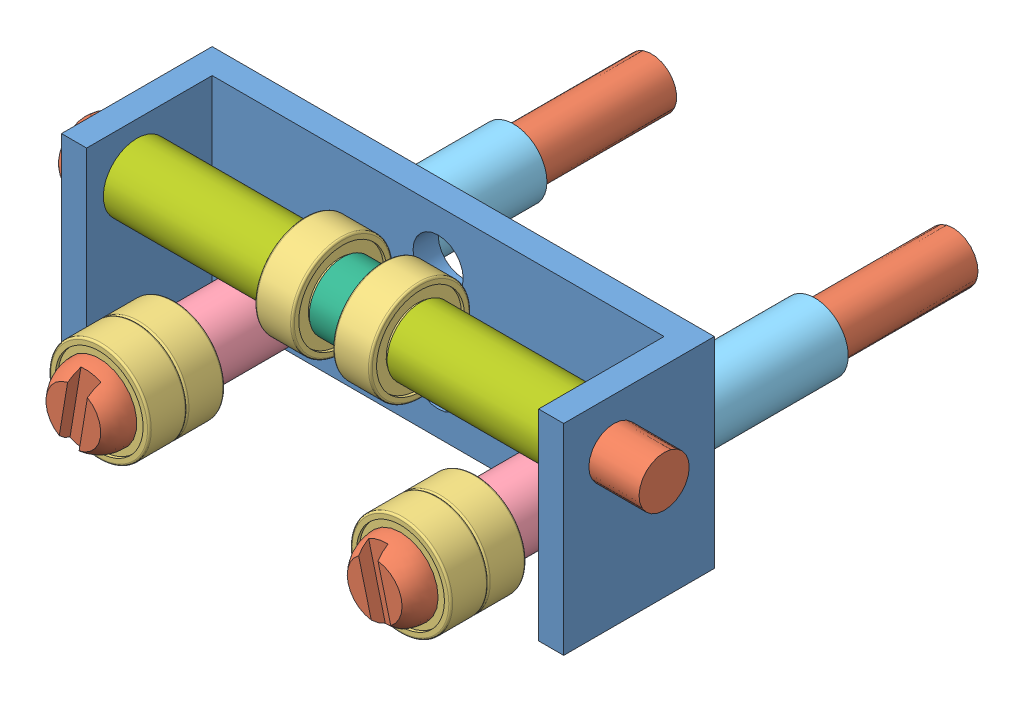
SolidWorks assembly BearingCarriageAssembly, configuration Default. Lengths in mm.
Overall size (73.12 33.5 73.12).
20 component instances, 7 part files, 6 mates.
Components (placement in the parent):
- BEARINGPLATECARRIAGE-1: BEARINGPLATECARRIAGE [Default] at (-2.2491 20.2622 55.3264) size (63.5 25.4 19.05)
- Elevator_Side_Bearing_Assembly-1: Elevator_Side_Bearing_Assembly [Default] at (1.1387 12.8485 -8.1602) x (0.986617 -0.163055 0) z (0 0 1) size (14.25 14.25 73.12)
  - .25-20 bolt-1: .25-20 bolt [Default] at (6.9434 15.0978 51.1041) size (9.53 9.53 73.12)
  - Radial_Bearing_0.5_inch-1: Radial_Bearing_0.5_inch [Default] at (6.9434 15.0978 69.0429) x (0 0 -1) z (0.028743 -0.999587 0) size (4.76 12.7 12.7)
  - Radial_Bearing_0.5_inch-2: Radial_Bearing_0.5_inch [Default] at (6.9434 15.0978 64.2804) x (0 0 -1) z (0.991417 0.130735 0) size (4.76 12.7 12.7)
  - Spacer_unknown_inch-1: Spacer_unknown_inch [Default] at (6.9434 15.0978 47.6116) size (8.47 8.47 14.29)
  - Spacer_1_inch-1: Spacer_1_inch [Default] at (6.9434 15.0978 19.0366) x (0.031956 -0.999489 0) z (0 0 1) size (8.47 8.47 25.4)
- Elevator_Side_Bearing_Assembly-2: Elevator_Side_Bearing_Assembly [Default] at (45.5783 10.2623 -8.1602) x (0.968614 0.24857 0) z (0 0 1) size (14.25 14.25 73.12)
  - .25-20 bolt-1: .25-20 bolt [Default] at (6.9434 15.0978 51.1041) size (9.53 9.53 73.12)
  - Radial_Bearing_0.5_inch-1: Radial_Bearing_0.5_inch [Default] at (6.9434 15.0978 69.0429) x (0 0 -1) z (0.028743 -0.999587 0) size (4.76 12.7 12.7)
  - Radial_Bearing_0.5_inch-2: Radial_Bearing_0.5_inch [Default] at (6.9434 15.0978 64.2804) x (0 0 -1) z (0.991417 0.130735 0) size (4.76 12.7 12.7)
  - Spacer_unknown_inch-1: Spacer_unknown_inch [Default] at (6.9434 15.0978 47.6116) size (8.47 8.47 14.29)
  - Spacer_1_inch-1: Spacer_1_inch [Default] at (6.9434 15.0978 19.0366) x (0.031956 -0.999489 0) z (0 0 1) size (8.47 8.47 25.4)
- Elevator_Front_Bearing_Assembly-1: Elevator_Front_Bearing_Assembly [Default] at (90.0541 0.483 75.7298) x (0 0.873605 0.486635) z (-1 0 0) size (17.82 17.82 73.12)
  - .25-20 bolt-1: .25-20 bolt [Default] at (20.9022 42.2675 71.9832) size (9.53 9.53 73.12)
  - Radial_Bearing_0.5_inch-1: Radial_Bearing_0.5_inch [Default] at (20.9022 42.2675 65.4744) x (0 0 -1) z (0.964421 -0.264372 0) size (4.76 12.7 12.7)
  - Radial_Bearing_0.5_inch-2: Radial_Bearing_0.5_inch [Default] at (20.9022 42.2675 55.6319) x (0 0 -1) z (0.788975 0.614426 0) size (4.76 12.7 12.7)
  - Spacer_0.2_inch-2: Spacer_0.2_inch [Default] at (20.9022 42.2675 58.0132) x (0.991317 0.131493 0) z (0 0 1) size (8.47 8.47 5.08)
  - Spacer_inch-1: Spacer_inch [Default] at (20.9022 42.2675 67.8557) x (0.114692 -0.993401 0) z (0 0 1) size (8.47 8.47 21.27)
  - Spacer_inch-2: Spacer_inch [Default] at (20.9022 42.2675 31.9782) x (-0.332332 -0.943163 0) z (0 0 1) size (8.47 8.47 21.27)
Mates (geometry in assembly coordinates):
- Concentric1: concentric anti-aligned: circle of BEARINGPLATECARRIAGE-1; circle of Elevator_Side_Bearing_Assembly-2/Spacer_unknown_inch-1
- Coincident2: coincident anti-aligned: plane of BEARINGPLATECARRIAGE-1 through (58.0759 45.6622 39.4514) normal (0 0 1); plane of Elevator_Side_Bearing_Assembly-2/Spacer_unknown_inch-1 through (48.5509 26.6122 39.4514) normal (0 0 -1)
- Concentric2: concentric anti-aligned: circle of BEARINGPLATECARRIAGE-1; circle of Elevator_Side_Bearing_Assembly-1/Spacer_unknown_inch-1
- Coincident4: coincident anti-aligned: plane of BEARINGPLATECARRIAGE-1 through (58.0759 45.6622 39.4514) normal (0 0 1); plane of Elevator_Side_Bearing_Assembly-1/Spacer_unknown_inch-1 through (10.4509 26.6122 39.4514) normal (0 0 -1)
- Concentric3: concentric anti-aligned: circle of BEARINGPLATECARRIAGE-1; circle of Elevator_Front_Bearing_Assembly-1/.25-20 bolt-1
- Coincident6: coincident anti-aligned: plane of BEARINGPLATECARRIAGE-1 through (-2.2491 45.6622 55.3264) normal (-1 0 0); plane of Elevator_Front_Bearing_Assembly-1/.25-20 bolt-1 through (-2.2491 39.3122 48.9764) normal (1 0 0)
